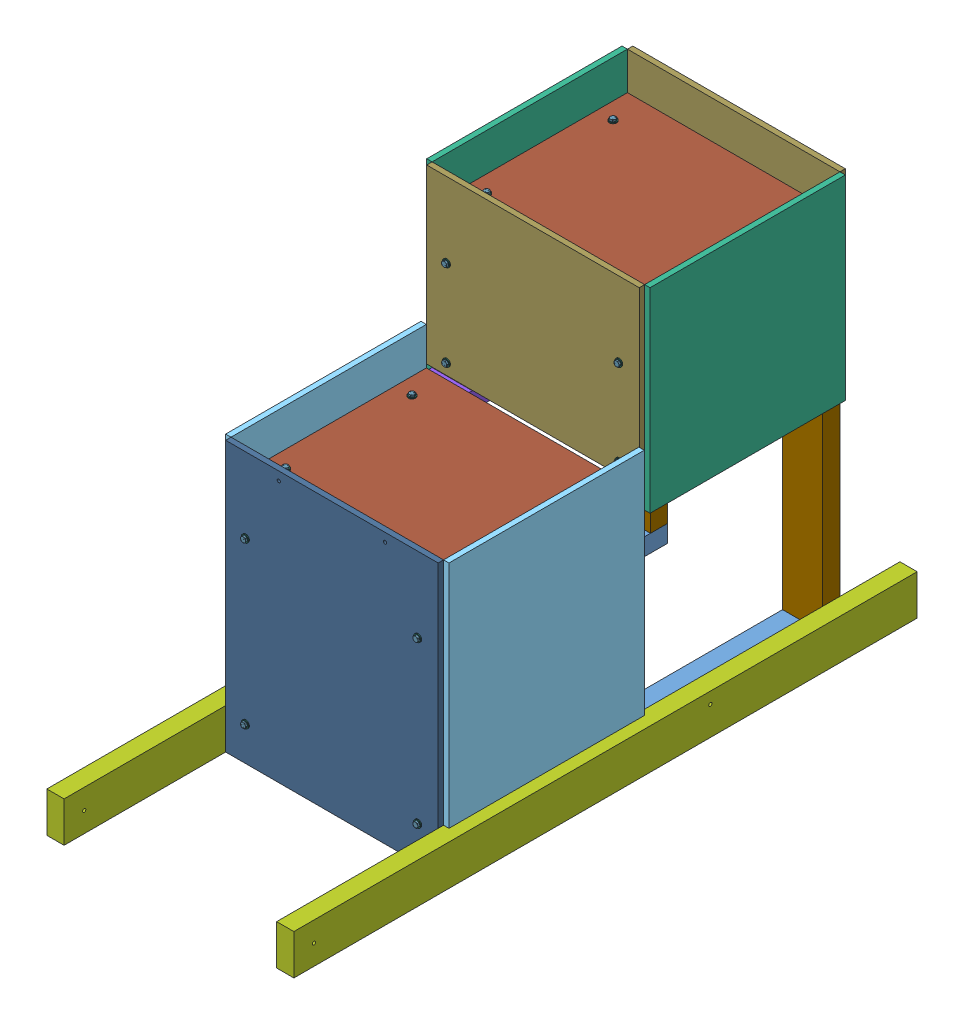
SolidWorks assembly Cube Shelf, configuration Default. Lengths in mm.
Overall size (546.1 901.7 1377.95).
85 component instances, 15 part files, 174 mates.
Components (placement in the parent):
- TE-23039-1: TE-23039 [Default] at (0 0 0.0635) size (127 901.7 1377.95)
  - TE-23018-1: TE-23018 [Default] at (44.45 19.05 -0.0635) x (0 -1 0) z (0 0 1) size (38.1 88.9 876.3)
  - TE-23019-1: TE-23019 [Default] at (44.45 469.9 857.1865) x (0 0 -1) z (0 -1 0) size (38.1 88.9 431.8)
  - TE-23023-1: TE-23023 [Default] at (44.45 793.75 -0.0635) x (0 -1 0) z (0 0 1) size (38.1 88.9 431.8)
  - TE-23022-1: TE-23022 [Default] at (44.45 508 412.6865) x (0 0 1) z (0 1 0) size (38.1 88.9 266.7)
  - TE-23024-1: TE-23024 [Default] at (-11.9062 342.9 660.3365) x (0 0 -1) z (0 -1 0) size (431.8 11.91 508)
  - TE-23025-1: TE-23025 [Default] at (-11.9062 685.8 215.8365) x (0 0 1) z (0 1 0) size (431.8 11.91 431.8)
  - TE-23005-1: TE-23005 [Default] at (-19.05 44.45 -132.6198) size (38.1 88.9 1377.95)
  - TE-23021-1: TE-23021 [Default] at (44.45 488.95 38.0365) x (0 1 0) z (0 0 1) size (38.1 88.9 838.2)
  - TE-23020-1: TE-23020 [Default] at (44.45 38.1 18.9865) x (0 0 -1) z (0 1 0) size (38.1 88.9 736.6)
- TE-23038-1: TE-23038 [Default] at (0 0 0.0635) size (127 901.7 1377.95)
  - TE-23018-1: TE-23018 [Default] at (425.45 19.05 -0.0635) x (0 -1 0) z (0 0 1) size (38.1 88.9 876.3)
  - TE-23019-1: TE-23019 [Default] at (425.45 38.1 857.1865) x (0 0 -1) z (0 1 0) size (38.1 88.9 431.8)
  - TE-23023-1: TE-23023 [Default] at (425.45 793.75 -0.0635) x (0 -1 0) z (0 0 1) size (38.1 88.9 431.8)
  - TE-23022-1: TE-23022 [Default] at (425.45 508 412.6865) x (0 0 1) z (0 1 0) size (38.1 88.9 266.7)
  - TE-23024-1: TE-23024 [Default] at (481.8062 342.9 660.3365) x (0 0 1) z (0 -1 0) size (431.8 11.91 508)
  - TE-23025-1: TE-23025 [Default] at (481.8062 685.8 215.8365) x (0 0 1) z (0 -1 0) size (431.8 11.91 431.8)
  - TE-23005-1: TE-23005 [Default] at (488.95 44.45 -132.6198) size (38.1 88.9 1377.95)
  - TE-23021-1: TE-23021 [Default] at (425.45 488.95 38.0365) x (0 1 0) z (0 0 1) size (38.1 88.9 838.2)
  - TE-23020-1: TE-23020 [Default] at (425.45 38.1 18.9865) x (0 0 -1) z (0 1 0) size (38.1 88.9 736.6)
- TE-23026-1: TE-23026 [Default] at (234.95 298.45 876.3) x (1 0 0) z (0 -1 0) size (469.9 11.91 596.9)
- TE-23027-1: TE-23027 [Default] at (234.95 508 660.4) size (457.2 11.91 419.1)
- TE-23028-1: TE-23028 [Default] at (234.95 711.2 431.8) size (469.9 381 11.91)
- TE-23028-2: TE-23028 [Default] at (234.95 711.2 -11.9062) size (469.9 381 11.91)
- TE-23027-2: TE-23027 [Default] at (234.95 812.8 215.9) size (457.2 11.91 419.1)
- TeeNut_.25_20-1: TeeNut_.25_20 [90975A025] at (425.45 736.6 392.5062) x (1 0 0) z (0 -1 0) size (19.05 9.53 19.05)
- TeeNut_.25_20-2: TeeNut_.25_20 [90975A025] at (425.45 546.1 392.5062) x (0.987351 0.158553 0) z (0.158553 -0.987351 0) size (19.05 9.53 19.05)
- TeeNut_.25_20-4: TeeNut_.25_20 [90975A025] at (425.45 773.5062 355.6) x (-0.994177 0 -0.107761) z (0.107761 0 -0.994177) size (19.05 9.53 19.05)
- TeeNut_.25_20-6: TeeNut_.25_20 [90975A025] at (425.45 773.5062 76.2) x (-0.972467 0 -0.233039) z (0.233039 0 -0.972467) size (19.05 9.53 19.05)
- TeeNut_.25_20-8: TeeNut_.25_20 [90975A025] at (425.45 736.6 39.2938) x (-0.642788 0.766044 0) z (-0.766044 -0.642788 0) size (19.05 9.53 19.05)
- TeeNut_.25_20-10: TeeNut_.25_20 [90975A025] at (425.45 468.7062 520.7) x (-0.089543 0 -0.995983) z (0.995983 0 -0.089543) size (19.05 9.53 19.05)
- TeeNut_.25_20-12: TeeNut_.25_20 [90975A025] at (425.45 468.7062 800.1) x (-0.194284 0 -0.980945) z (0.980945 0 -0.194284) size (19.05 9.53 19.05)
- TeeNut_.25_20-14: TeeNut_.25_20 [90975A025] at (425.45 431.8 837.0062) x (0.939693 0.34202 0) z (0.34202 -0.939693 0) size (19.05 9.53 19.05)
- TeeNut_.25_20-16: TeeNut_.25_20 [90975A025] at (425.45 76.2 837.0062) x (0.984808 0.173648 0) z (0.173648 -0.984808 0) size (19.05 9.53 19.05)
- TeeNut_.25_20-18: TeeNut_.25_20 [90975A025] at (44.45 76.2 837.0062) x (1 0 0) z (0 -1 0) size (19.05 9.53 19.05)
- TeeNut_.25_20-20: TeeNut_.25_20 [90975A025] at (44.45 431.8 837.0062) x (0.984808 -0.173648 0) z (-0.173648 -0.984808 0) size (19.05 9.53 19.05)
- TeeNut_.25_20-22: TeeNut_.25_20 [90975A025] at (44.45 468.7062 800.1) x (0.430036 0 -0.902812) z (0.902812 0 0.430036) size (19.05 9.53 19.05)
- TeeNut_.25_20-24: TeeNut_.25_20 [90975A025] at (44.45 468.7062 520.7) x (0.645562 0 -0.763708) z (0.763708 0 0.645562) size (19.05 9.53 19.05)
- TeeNut_.25_20-26: TeeNut_.25_20 [90975A025] at (44.45 546.1 392.5062) x (0.902849 -0.429957 0) z (-0.429957 -0.902849 0) size (19.05 9.53 19.05)
- TeeNut_.25_20-28: TeeNut_.25_20 [90975A025] at (44.45 736.6 392.5062) x (0.906989 -0.421154 0) z (-0.421154 -0.906989 0) size (19.05 9.53 19.05)
- TeeNut_.25_20-30: TeeNut_.25_20 [90975A025] at (44.45 773.5062 355.6) x (-0.404582 0 -0.914502) z (0.914502 0 -0.404582) size (19.05 9.53 19.05)
- TeeNut_.25_20-32: TeeNut_.25_20 [90975A025] at (44.45 773.5062 76.2) x (-0.712248 0 -0.701928) z (0.701928 0 -0.712248) size (19.05 9.53 19.05)
- TeeNut_.25_20-34: TeeNut_.25_20 [90975A025] at (44.45 736.6 39.2938) x (-0.173648 -0.984808 0) z (0.984808 -0.173648 0) size (19.05 9.53 19.05)
- TeeNut_.25_20-36: TeeNut_.25_20 [90975A025] at (44.45 546.1 39.2938) x (-0.923728 -0.383049 0) z (0.383049 -0.923728 0) size (19.05 9.53 19.05)
- TeeNut_.25_20-38: TeeNut_.25_20 [90975A025] at (425.45 546.1 39.2938) x (0.173648 -0.984808 0) z (0.984808 0.173648 0) size (19.05 9.53 19.05)
- hex_.25_20_2-2: hex_.25_20_2 [Default] at (425.45 546.1 9.4774) x (0 0 1) z (-0.763011 -0.646385 0) size (54.77 12.83 11.11)
- hex_.25_20_2-3: hex_.25_20_2 [Default] at (425.45 736.6 9.4774) x (0 0 1) z (0.496833 0.867846 0) size (54.77 12.83 11.11)
- hex_.25_20_2-4: hex_.25_20_2 [Default] at (44.45 546.1 9.4774) x (0 0 1) z (-0.44479 -0.895635 0) size (54.77 12.83 11.11)
- hex_.25_20_2-5: hex_.25_20_2 [Default] at (44.45 803.3226 76.2) x (0 -1 0) z (-0.809763 0 0.586757) size (54.77 12.83 11.11)
- hex_.25_20_2-6: hex_.25_20_2 [Default] at (425.45 431.8 866.8226) x (0 0 -1) z (-0.990347 -0.138607 0) size (54.77 12.83 11.11)
- hex_.25_20_2-7: hex_.25_20_2 [Default] at (425.45 76.2 866.8226) x (0 0 -1) z (0.745154 -0.666893 0) size (54.77 12.83 11.11)
- hex_.25_20_2-8: hex_.25_20_2 [Default] at (425.45 803.3226 76.2) x (0 -1 0) z (-0.954468 0 0.298314) size (54.77 12.83 11.11)
- hex_.25_20_2-9: hex_.25_20_2 [Default] at (44.45 76.2 866.8226) x (0 0 -1) z (-0.848403 -0.52935 0) size (54.77 12.83 11.11)
- hex_.25_20_2-10: hex_.25_20_2 [Default] at (44.45 431.8 866.8226) x (0 0 -1) z (0.285323 0.958431 0) size (54.77 12.83 11.11)
- hex_.25_20_2-11: hex_.25_20_2 [Default] at (425.45 498.5226 520.7) x (0 -1 0) z (0.273056 0 0.961998) size (54.77 12.83 11.11)
- hex_.25_20_2-12: hex_.25_20_2 [Default] at (425.45 498.5226 800.1) x (0 -1 0) z (-0.907887 0 0.419215) size (54.77 12.83 11.11)
- hex_.25_20_2-13: hex_.25_20_2 [Default] at (44.45 803.3226 355.6) x (0 -1 0) z (0.603096 0 0.797669) size (54.77 12.83 11.11)
- hex_.25_20_2-15: hex_.25_20_2 [Default] at (425.45 546.1 422.3226) x (0 0 -1) z (0.807696 -0.5896 0) size (54.77 12.83 11.11)
- hex_.25_20_2-16: hex_.25_20_2 [Default] at (44.45 498.5226 800.1) x (0 -1 0) z (0.961687 0 0.274151) size (54.77 12.83 11.11)
- hex_.25_20_2-17: hex_.25_20_2 [Default] at (44.45 498.5226 520.7) x (0 -1 0) z (-0.90705 0 0.421023) size (54.77 12.83 11.11)
- hex_.25_20_2-18: hex_.25_20_2 [Default] at (44.45 546.1 422.3226) x (0 0 -1) z (0.948389 -0.31711 0) size (54.77 12.83 11.11)
- hex_.25_20_2-19: hex_.25_20_2 [Default] at (425.45 803.3226 355.6) x (0 -1 0) z (-0.287086 0 0.957905) size (54.77 12.83 11.11)
- hex_.25_20_2-20: hex_.25_20_2 [Default] at (44.45 736.6 422.3226) x (0 0 -1) z (1 0 0) size (54.77 12.83 11.11)
- hex_.25_20_2-1: hex_.25_20_2 [Default] at (425.45 736.6 422.3226) x (0 0 -1) z (-0.132102 0.991236 0) size (54.77 12.83 11.11)
- washer_flat_.25-1: washer_flat_.25 [98023A029] at (425.45 736.6 -13.9383) x (1 0 0) z (0 -1 0) size (15.88 2.03 15.88)
- washer_flat_.25-2: washer_flat_.25 [98023A029] at (425.45 521.9383 520.7) x (-0.837169 0 -0.546944) z (-0.546944 0 0.837169) size (15.88 2.03 15.88)
- washer_flat_.25-3: washer_flat_.25 [98023A029] at (425.45 521.9383 800.1) x (-0.837169 0 -0.546944) z (-0.546944 0 0.837169) size (15.88 2.03 15.88)
- washer_flat_.25-4: washer_flat_.25 [98023A029] at (44.45 826.7382 355.6) x (-0.837169 0 -0.546944) z (-0.546944 0 0.837169) size (15.88 2.03 15.88)
- washer_flat_.25-5: washer_flat_.25 [98023A029] at (44.45 521.9383 520.7) x (-0.837169 0 -0.546944) z (-0.546944 0 0.837169) size (15.88 2.03 15.88)
- washer_flat_.25-6: washer_flat_.25 [98023A029] at (44.45 431.8 890.2382) x (1 0 0) z (0 1 0) size (15.88 2.03 15.88)
- washer_flat_.25-7: washer_flat_.25 [98023A029] at (425.45 736.6 445.7382) x (0.995174 0.098126 0) z (-0.098126 0.995174 0) size (15.88 2.03 15.88)
- washer_flat_.25-8: washer_flat_.25 [98023A029] at (425.45 826.7382 76.2) x (-0.837169 0 -0.546944) z (-0.546944 0 0.837169) size (15.88 2.03 15.88)
- washer_flat_.25-9: washer_flat_.25 [98023A029] at (44.45 826.7382 76.2) x (-0.837169 0 -0.546944) z (-0.546944 0 0.837169) size (15.88 2.03 15.88)
- washer_flat_.25-10: washer_flat_.25 [98023A029] at (425.45 546.1 -13.9383) x (1 0 0) z (0 -1 0) size (15.88 2.03 15.88)
- washer_flat_.25-11: washer_flat_.25 [98023A029] at (44.45 546.1 -13.9383) x (1 0 0) z (0 -1 0) size (15.88 2.03 15.88)
- washer_flat_.25-12: washer_flat_.25 [98023A029] at (44.45 736.6 -13.9383) x (1 0 0) z (0 -1 0) size (15.88 2.03 15.88)
- washer_flat_.25-13: washer_flat_.25 [98023A029] at (425.45 431.8 890.2382) x (1 0 0) z (0 1 0) size (15.88 2.03 15.88)
- washer_flat_.25-14: washer_flat_.25 [98023A029] at (44.45 521.9383 800.1) x (-0.837169 0 -0.546944) z (-0.546944 0 0.837169) size (15.88 2.03 15.88)
- washer_flat_.25-15: washer_flat_.25 [98023A029] at (44.45 76.2 890.2382) x (1 0 0) z (0 1 0) size (15.88 2.03 15.88)
- washer_flat_.25-16: washer_flat_.25 [98023A029] at (425.45 826.7382 355.6) x (-0.837169 0 -0.546944) z (-0.546944 0 0.837169) size (15.88 2.03 15.88)
- washer_flat_.25-17: washer_flat_.25 [98023A029] at (425.45 76.2 890.2382) x (1 0 0) z (0 1 0) size (15.88 2.03 15.88)
- washer_flat_.25-18: washer_flat_.25 [98023A029] at (425.45 546.1 445.7382) x (0.860134 -0.510068 0) z (0.510068 0.860134 0) size (15.88 2.03 15.88)
- washer_flat_.25-19: washer_flat_.25 [98023A029] at (44.45 546.1 445.7382) x (1 0 0) z (0 1 0) size (15.88 2.03 15.88)
- washer_flat_.25-20: washer_flat_.25 [98023A029] at (44.45 736.6 445.7382) x (0.975112 0.221713 0) z (-0.221713 0.975112 0) size (15.88 2.03 15.88)
- hex_.25_20_2-21: hex_.25_20_2 [Default] at (44.45 736.6 9.4774) x (0 0 1) z (0.942994 -0.332808 0) size (54.77 12.83 11.11)
Mates (geometry in assembly coordinates):
- Distance5: distance = 6.35 mm anti-aligned: plane of TE-23026-1 through (234.95 298.45 876.3) normal (0 0 -1); plane of Cube Shelf Platform-1 through (6.35 519.9062 869.95) normal (0 0 1)
- Coincident83: coincident aligned: plane of Cube Shelf Upper Front Panel-1 through (0 901.7 443.7063) normal (0 1 0); plane of Cube Shelf Upper Front Panel-2 through (0 901.7 0) normal (0 1 0)
- Coincident159: coincident anti-aligned: plane of Cube Shelf Right Side Frame-1/Cube Shelf Long Horizontal-1 through (0 0 876.3) normal (0 -1 0)
- Coincident160: coincident anti-aligned: plane of Cube Shelf Right Side Frame-1/Cube Shelf Long Horizontal-1 through (0 38.1 876.3) normal (-1 0 0)
- Coincident161: coincident anti-aligned: plane of Cube Shelf Right Side Frame-1/Cube Shelf Long Horizontal-1 through (44.45 19.05 0) normal (0 0 -1)
- Coincident162: coincident aligned: plane of Cube Shelf Right Side Frame-1/Cube Shelf Long Horizontal-1 through (0 0 876.3) normal (0 -1 0); plane of TE-23026-1 through (0 0 888.2062) normal (0 -1 0)
- Coincident163: coincident anti-aligned: plane of TE-23039-1/TE-23019-1 through (0 38.1 876.3) normal (0 0 1); plane of TE-23026-1 through (234.95 298.45 876.3) normal (0 0 -1)
- Coincident164: coincident aligned: plane of TE-23039-1/TE-23019-1 through (0 38.1 876.3) normal (-1 0 0); plane of TE-23026-1 through (0 0 888.2062) normal (-1 0 0)
- Distance12: distance = 6.35 mm anti-aligned: plane of Cube Shelf Platform-1 through (6.35 519.9062 869.95) normal (-1 0 0); plane of TE-23039-1/TE-23024-1 through (0 342.9 660.4) normal (1 0 0)
- Coincident166: coincident aligned: plane of Cube Shelf Upper Front Panel-1 through (0 901.7 443.7063) normal (0 1 0); plane of TE-23039-1/TE-23025-1 through (0 901.7 0) normal (0 1 0)
- Coincident167: coincident anti-aligned: plane of Cube Shelf Upper Front Panel-2 through (234.95 711.2 0) normal (0 0 1); plane of TE-23039-1/TE-23025-1 through (0 901.7 0) normal (0 0 -1)
- Coincident168: coincident anti-aligned: plane of Cube Shelf Upper Front Panel-1 through (234.95 711.2 431.8) normal (0 0 -1); plane of TE-23039-1/TE-23025-1 through (0 901.7 431.8) normal (0 0 1)
- Coincident181: coincident aligned: plane of Assem7^Cube Shelf-1/Copy of Assem6^Assem7_Cube Shelf-1/Cube Shelf Long Horizontal-1 through (381 0 876.3) normal (0 -1 0); plane of TE-23026-1 through (0 0 888.2062) normal (0 -1 0)
- Coincident182: coincident anti-aligned: plane of Assem7^Cube Shelf-1/Copy of Assem6^Assem7_Cube Shelf-1/Cube Shelf Long Vertical-1 through (469.9 482.6 876.3) normal (0 0 1); plane of TE-23026-1 through (234.95 298.45 876.3) normal (0 0 -1)
- Coincident183: coincident aligned: plane of Assem7^Cube Shelf-1/Copy of Assem6^Assem7_Cube Shelf-1/Cube Shelf Short Horizontal-1 through (469.9 812.8 431.8) normal (1 0 0); plane of TE-23028-2 through (469.9 520.7 0) normal (1 0 0)
- Coincident184: coincident anti-aligned: plane of Assem7^Cube Shelf-1/Copy of Assem6^Assem7_Cube Shelf-1/Cube Shelf Short Horizontal-1 through (381 812.8 431.8) normal (0 1 0); plane of GE-23651-2 through (234.95 812.8 215.9) normal (0 -1 0)
- Concentric5: concentric anti-aligned: cylinder of Assem7^Cube Shelf-1/Copy of Assem6^Assem7_Cube Shelf-1/Cube Shelf Short Horizontal-1 through (425.45 774.7 76.2) axis (0 -1 0) radius 3.9688; cylinder of GE-23651-2 through (425.45 824.7062 76.2) axis (0 1 0) radius 3.5719
- Coincident185: coincident anti-aligned: plane of Assem7^Cube Shelf-1/Copy of Assem6^Assem7_Cube Shelf-1/Cube Shelf Short Vertical-1 through (381 774.7 431.8) normal (0 0 1); plane of TE-23028-1 through (234.95 711.2 431.8) normal (0 0 -1)
- Coincident186: coincident aligned: plane of Assem7^Cube Shelf-1/Copy of Assem6^Assem7_Cube Shelf-1/Cube Shelf Short Vertical-1 through (469.9 774.7 393.7) normal (1 0 0); plane of TE-23028-1 through (469.9 520.7 443.7063) normal (1 0 0)
- Coincident187: coincident anti-aligned: plane of TE-23028-1 through (234.95 711.2 443.7063) normal (0 0 1); plane of Assem7^Cube Shelf-1/Copy of Assem6^Assem7_Cube Shelf-1/Cube Shelf Lower Side Panel-1 through (469.9 88.9 443.7063) normal (0 0 -1)
- Coincident188: coincident aligned: plane of TE-23028-2 through (0 901.7 0) normal (0 1 0); plane of Assem7^Cube Shelf-1/Copy of Assem6^Assem7_Cube Shelf-1/Cube Shelf Upper Side Panel-1 through (469.9 901.7 0) normal (0 1 0)
- Coincident189: coincident anti-aligned: plane of TE-23028-2 through (234.95 711.2 0) normal (0 0 1); plane of Assem7^Cube Shelf-1/Copy of Assem6^Assem7_Cube Shelf-1/Cube Shelf Upper Side Panel-1 through (469.9 482.6 0) normal (0 0 -1)
- Coincident190: coincident anti-aligned: plane of TE-23026-1 through (469.9 0 888.2062) normal (1 0 0); plane of Assem7^Cube Shelf-1/Copy of Assem6^Assem7_Cube Shelf-1/Cone Ramp Horizontal no holes-1 through (469.9 0 1245.3302) normal (-1 0 0)
- Concentric7: concentric anti-aligned: cylinder of Cube Shelf Left Side Frame-1/Copy of Assem6^Cube Shelf Left Side Frame-1/Cube Shelf Short Vertical-1 through (425.45 736.6 431.8) axis (0 0 1) radius 3.9688; cylinder of TeeNut_.25_20-1 through (425.45 736.6 401.6375) axis (0 0 -1) radius 3.8735
- Coincident191: coincident anti-aligned: plane of Cube Shelf Left Side Frame-1/Copy of Assem6^Cube Shelf Left Side Frame-1/Cube Shelf Short Vertical-1 through (381 774.7 393.7) normal (0 0 -1); plane of TeeNut_.25_20-1 through (425.45 736.6 393.7) normal (0 0 1)
- Coincident192: coincident anti-aligned: plane of Cube Shelf Left Side Frame-1/Copy of Assem6^Cube Shelf Left Side Frame-1/Cube Shelf Long Horizontal top-1 through (469.9 520.7 876.3) normal (0 1 0); plane of TE-23027-1 through (234.95 508 660.4) normal (0 -1 0)
- Concentric8: concentric anti-aligned: cylinder of Cube Shelf Left Side Frame-1/Copy of Assem6^Cube Shelf Left Side Frame-1/Cube Shelf Short Vertical-1 through (425.45 558.8 431.8) axis (0 0 1) radius 3.9688; cylinder of TeeNut_.25_20-2 through (425.45 546.1 401.6375) axis (0 0 -1) radius 3.8735
- Coincident193: coincident anti-aligned: plane of Cube Shelf Left Side Frame-1/Copy of Assem6^Cube Shelf Left Side Frame-1/Cube Shelf Short Vertical-1 through (381 774.7 393.7) normal (0 0 -1); plane of TeeNut_.25_20-2 through (425.45 546.1 393.7) normal (0 0 1)
- Concentric9: concentric aligned: cylinder of Cube Shelf Left Side Frame-1/Copy of Assem6^Cube Shelf Left Side Frame-1/Cube Shelf Short Horizontal-1 through (425.45 774.7 355.6) axis (0 -1 0) radius 3.9688; cylinder of TeeNut_.25_20-4 through (425.45 782.6375 355.6) axis (0 -1 0) radius 3.8735
- Coincident194: coincident anti-aligned: plane of Cube Shelf Left Side Frame-1/Copy of Assem6^Cube Shelf Left Side Frame-1/Cube Shelf Short Horizontal-1 through (381 774.7 431.8) normal (0 -1 0); plane of TeeNut_.25_20-4 through (425.45 774.7 355.6) normal (0 1 0)
- Concentric10: concentric aligned: cylinder of Cube Shelf Left Side Frame-1/Copy of Assem6^Cube Shelf Left Side Frame-1/Cube Shelf Short Horizontal-1 through (425.45 774.7 76.2) axis (0 -1 0) radius 3.9688; cylinder of TeeNut_.25_20-6 through (425.45 782.6375 76.2) axis (0 -1 0) radius 3.8735
- Coincident195: coincident anti-aligned: plane of Cube Shelf Left Side Frame-1/Copy of Assem6^Cube Shelf Left Side Frame-1/Cube Shelf Short Horizontal-1 through (381 774.7 431.8) normal (0 -1 0); plane of TeeNut_.25_20-6 through (425.45 774.7 76.2) normal (0 1 0)
- Concentric11: concentric anti-aligned: cylinder of Cube Shelf Left Side Frame-1/Copy of Assem6^Cube Shelf Left Side Frame-1/Back CS uprights-1 through (425.45 736.6 0) axis (0 0 -1) radius 3.9688; cylinder of TeeNut_.25_20-8 through (425.45 736.6 30.1625) axis (0 0 1) radius 3.8735
- Coincident196: coincident anti-aligned: plane of Cube Shelf Left Side Frame-1/Copy of Assem6^Cube Shelf Left Side Frame-1/Back CS uprights-1 through (469.9 774.7 38.1) normal (0 0 1); plane of TeeNut_.25_20-8 through (425.45 736.6 38.1) normal (0 0 -1)
- Concentric12: concentric anti-aligned: cylinder of Cube Shelf Left Side Frame-1/Copy of Assem6^Cube Shelf Left Side Frame-1/Cube Shelf Long Horizontal top-1 through (425.45 520.7 520.7) axis (0 1 0) radius 3.9688; cylinder of TeeNut_.25_20-10 through (425.45 477.8375 520.7) axis (0 -1 0) radius 3.8735
- Coincident197: coincident anti-aligned: plane of Cube Shelf Left Side Frame-1/Copy of Assem6^Cube Shelf Left Side Frame-1/Cube Shelf Long Horizontal top-1 through (469.9 482.6 876.3) normal (0 -1 0); plane of TeeNut_.25_20-10 through (425.45 469.9 520.7) normal (0 1 0)
- Concentric13: concentric anti-aligned: cylinder of Cube Shelf Left Side Frame-1/Copy of Assem6^Cube Shelf Left Side Frame-1/Cube Shelf Long Horizontal top-1 through (425.45 520.7 800.1) axis (0 1 0) radius 3.9688; cylinder of TeeNut_.25_20-12 through (425.45 477.8375 800.1) axis (0 -1 0) radius 3.8735
- Coincident198: coincident anti-aligned: plane of Cube Shelf Left Side Frame-1/Copy of Assem6^Cube Shelf Left Side Frame-1/Cube Shelf Long Horizontal top-1 through (469.9 482.6 876.3) normal (0 -1 0); plane of TeeNut_.25_20-12 through (425.45 469.9 800.1) normal (0 1 0)
- Concentric14: concentric aligned: cylinder of Cube Shelf Left Side Frame-1/Copy of Assem6^Cube Shelf Left Side Frame-1/Cube Shelf Long Vertical-1 through (425.45 444.5 838.2) axis (0 0 -1) radius 3.9688; cylinder of TeeNut_.25_20-14 through (425.45 431.8 846.1375) axis (0 0 -1) radius 3.8735
- Coincident199: coincident anti-aligned: plane of Cube Shelf Left Side Frame-1/Copy of Assem6^Cube Shelf Left Side Frame-1/Cube Shelf Long Vertical-1 through (469.9 482.6 838.2) normal (0 0 -1); plane of TeeNut_.25_20-14 through (425.45 431.8 838.2) normal (0 0 1)
- Concentric15: concentric aligned: cylinder of Cube Shelf Left Side Frame-1/Copy of Assem6^Cube Shelf Left Side Frame-1/Cube Shelf Long Vertical-1 through (425.45 76.2 838.2) axis (0 0 -1) radius 3.9688; cylinder of TeeNut_.25_20-16 through (425.45 76.2 846.1375) axis (0 0 -1) radius 3.8735
- Coincident200: coincident anti-aligned: plane of Cube Shelf Left Side Frame-1/Copy of Assem6^Cube Shelf Left Side Frame-1/Cube Shelf Long Vertical-1 through (469.9 482.6 838.2) normal (0 0 -1); plane of TeeNut_.25_20-16 through (425.45 76.2 838.2) normal (0 0 1)
- Concentric16: concentric aligned: cylinder of TE-23039-1/TE-23019-1 through (44.45 76.2 838.2) axis (0 0 -1) radius 3.9688; cylinder of TeeNut_.25_20-18 through (44.45 76.2 846.1375) axis (0 0 -1) radius 3.8735
- Coincident201: coincident anti-aligned: plane of TE-23039-1/TE-23019-1 through (0 38.1 838.2) normal (0 0 -1); plane of TeeNut_.25_20-18 through (44.45 76.2 838.2) normal (0 0 1)
- Concentric17: concentric aligned: cylinder of TE-23039-1/TE-23019-1 through (44.45 431.8 838.2) axis (0 0 -1) radius 3.9688; cylinder of TeeNut_.25_20-20 through (44.45 431.8 846.1375) axis (0 0 -1) radius 3.8735
- Coincident202: coincident anti-aligned: plane of TE-23039-1/TE-23019-1 through (0 38.1 838.2) normal (0 0 -1); plane of TeeNut_.25_20-20 through (44.45 431.8 838.2) normal (0 0 1)
- Concentric18: concentric anti-aligned: cylinder of TE-23039-1/TE-23021-1 through (44.45 508 800.1) axis (0 1 0) radius 3.9688; cylinder of TeeNut_.25_20-22 through (44.45 477.8375 800.1) axis (0 -1 0) radius 3.8735
- Coincident203: coincident anti-aligned: plane of TE-23039-1/TE-23021-1 through (88.9 469.9 876.3) normal (0 -1 0); plane of TeeNut_.25_20-22 through (44.45 469.9 800.1) normal (0 1 0)
- Concentric19: concentric anti-aligned: cylinder of TE-23039-1/TE-23021-1 through (44.45 508 520.7) axis (0 1 0) radius 3.9688; cylinder of TeeNut_.25_20-24 through (44.45 477.8375 520.7) axis (0 -1 0) radius 3.8735
- Coincident204: coincident anti-aligned: plane of TE-23039-1/TE-23021-1 through (88.9 469.9 876.3) normal (0 -1 0); plane of TeeNut_.25_20-24 through (44.45 469.9 520.7) normal (0 1 0)
- Concentric20: concentric anti-aligned: cylinder of TE-23039-1/TE-23022-1 through (44.45 546.1 431.8) axis (0 0 1) radius 3.9688; cylinder of TeeNut_.25_20-26 through (44.45 546.1 401.6375) axis (0 0 -1) radius 3.8735
- Coincident205: coincident anti-aligned: plane of TE-23039-1/TE-23022-1 through (0 774.7 393.7) normal (0 0 -1); plane of TeeNut_.25_20-26 through (44.45 546.1 393.7) normal (0 0 1)
- Concentric21: concentric anti-aligned: cylinder of TE-23039-1/TE-23022-1 through (44.45 736.6 431.8) axis (0 0 1) radius 3.9688; cylinder of TeeNut_.25_20-28 through (44.45 736.6 401.6375) axis (0 0 -1) radius 3.8735
- Coincident206: coincident anti-aligned: plane of TE-23039-1/TE-23022-1 through (0 774.7 393.7) normal (0 0 -1); plane of TeeNut_.25_20-28 through (44.45 736.6 393.7) normal (0 0 1)
- Concentric22: concentric aligned: cylinder of Cube Shelf Right Side Frame-1/Cube Shelf Short Horizontal-1 through (44.45 774.7 355.6) axis (0 -1 0) radius 3.9688; cylinder of TeeNut_.25_20-30 through (44.45 782.6375 355.6) axis (0 -1 0) radius 3.8735
- Coincident207: coincident anti-aligned: plane of Cube Shelf Right Side Frame-1/Cube Shelf Short Horizontal-1 through (0 774.7 431.8) normal (0 -1 0); plane of TeeNut_.25_20-30 through (44.45 774.7 355.6) normal (0 1 0)
- Concentric23: concentric aligned: cylinder of Cube Shelf Right Side Frame-1/Cube Shelf Short Horizontal-1 through (44.45 774.7 76.2) axis (0 -1 0) radius 3.9688; cylinder of TeeNut_.25_20-32 through (44.45 782.6375 76.2) axis (0 -1 0) radius 3.8735
- Coincident208: coincident anti-aligned: plane of Cube Shelf Right Side Frame-1/Cube Shelf Short Horizontal-1 through (0 774.7 431.8) normal (0 -1 0); plane of TeeNut_.25_20-32 through (44.45 774.7 76.2) normal (0 1 0)
- Concentric24: concentric anti-aligned: cylinder of Cube Shelf Right Side Frame-1/Back CS uprights-1 through (44.45 736.6 0) axis (0 0 -1) radius 3.9688; cylinder of TeeNut_.25_20-34 through (44.45 736.6 30.1625) axis (0 0 1) radius 3.8735
- Coincident209: coincident anti-aligned: plane of Cube Shelf Right Side Frame-1/Back CS uprights-1 through (88.9 774.7 38.1) normal (0 0 1); plane of TeeNut_.25_20-34 through (44.45 736.6 38.1) normal (0 0 -1)
- Concentric25: concentric anti-aligned: cylinder of Cube Shelf Right Side Frame-1/Back CS uprights-1 through (44.45 546.1 0) axis (0 0 -1) radius 3.9688; cylinder of TeeNut_.25_20-36 through (44.45 546.1 30.1625) axis (0 0 1) radius 3.8735
- Coincident210: coincident anti-aligned: plane of Cube Shelf Right Side Frame-1/Back CS uprights-1 through (88.9 774.7 38.1) normal (0 0 1); plane of TeeNut_.25_20-36 through (44.45 546.1 38.1) normal (0 0 -1)
- Concentric26: concentric anti-aligned: cylinder of Cube Shelf Left Side Frame-1/Copy of Assem6^Cube Shelf Left Side Frame-1/Back CS uprights-1 through (425.45 558.8 0) axis (0 0 -1) radius 3.9688; cylinder of TeeNut_.25_20-38 through (425.45 546.1 30.1625) axis (0 0 1) radius 3.8735
- Coincident211: coincident anti-aligned: plane of Cube Shelf Left Side Frame-1/Copy of Assem6^Cube Shelf Left Side Frame-1/Back CS uprights-1 through (469.9 774.7 38.1) normal (0 0 1); plane of TeeNut_.25_20-38 through (425.45 546.1 38.1) normal (0 0 -1)
- Coincident232: coincident anti-aligned: plane of TE-23038-1/TE-23021-1 through (469.9 508 876.3) normal (0 1 0); plane of TE-23027-1 through (234.95 508 660.4) normal (0 -1 0)
- Coincident233: coincident anti-aligned: plane of TE-23039-1/TE-23021-1 through (88.9 508 876.3) normal (0 1 0); plane of TE-23027-1 through (234.95 508 660.4) normal (0 -1 0)
- Coincident234: coincident anti-aligned: plane of TE-23039-1/TE-23025-1 through (0 685.8 215.9) normal (1 0 0); plane of Cube Shelf Upper Front Panel-1 through (0 520.7 443.7063) normal (-1 0 0)
- Coincident235: coincident anti-aligned: plane of Cube Shelf Right Side Frame-1/Cube Shelf Short Horizontal-1 through (0 812.8 431.8) normal (0 1 0); plane of GE-23651-2 through (234.95 812.8 215.9) normal (0 -1 0)
- Coincident237: coincident anti-aligned: plane of TE-23039-1/TE-23025-1 through (0 685.8 215.9) normal (1 0 0); plane of Cube Shelf Upper Front Panel-2 through (0 520.7 0) normal (-1 0 0)
- Coincident238: coincident aligned: plane of Cube Shelf Right Side Frame-1/Cone Ramp Horizontal no holes-1 through (-19.05 44.45 -132.5562) normal (0 0 -1); plane of Cube Shelf Left Side Frame-1/Cone Ramp Horizontal no holes-1 through (488.95 44.45 -132.5562) normal (0 0 -1)
- Coincident239: coincident aligned: plane of Cube Shelf Right Side Frame-1/Cone Ramp Horizontal no holes-1 through (-38.1 0 1245.3938) normal (0 -1 0); plane of Cube Shelf Left Side Frame-1/Cone Ramp Horizontal no holes-1 through (469.9 0 1245.3938) normal (0 -1 0)
- Coincident240: coincident anti-aligned: plane of TE-23038-1/TE-23024-1 through (469.9 342.9 660.4) normal (-1 0 0); plane of TE-23026-1 through (469.9 0 888.2062) normal (1 0 0)
- Concentric50: concentric anti-aligned: cylinder of Cube Shelf Left Side Frame-1/Back CS uprights-1 through (425.45 546.1 0) axis (0 0 -1) radius 3.9688; cylinder of TeeNut_.25_20-38 through (425.45 546.1 30.1625) axis (0 0 1) radius 3.8735
- Coincident241: coincident anti-aligned: plane of Cube Shelf Left Side Frame-1/Back CS uprights-1 through (469.9 774.7 38.1) normal (0 0 1); plane of TeeNut_.25_20-38 through (425.45 546.1 38.1) normal (0 0 -1)
- Concentric51: concentric anti-aligned: cylinder of TE-23038-1/TE-23022-1 through (425.45 736.6 431.8) axis (0 0 1) radius 3.9688; cylinder of TeeNut_.25_20-1 through (425.45 736.6 401.6375) axis (0 0 -1) radius 3.8735
- Coincident242: coincident anti-aligned: plane of TE-23038-1/TE-23022-1 through (381 774.7 393.7) normal (0 0 -1); plane of TeeNut_.25_20-1 through (425.45 736.6 393.7) normal (0 0 1)
- Concentric52: concentric anti-aligned: cylinder of TE-23038-1/TE-23022-1 through (425.45 546.1 431.8) axis (0 0 1) radius 3.9688; cylinder of TeeNut_.25_20-2 through (425.45 546.1 401.6375) axis (0 0 -1) radius 3.8735
- Coincident243: coincident anti-aligned: plane of TE-23038-1/TE-23022-1 through (381 774.7 393.7) normal (0 0 -1); plane of TeeNut_.25_20-2 through (425.45 546.1 393.7) normal (0 0 1)
- Concentric53: concentric aligned: cylinder of GE-23640-1/GE-23647-1 through (425.45 774.7 355.6) axis (0 -1 0) radius 3.9688; cylinder of TeeNut_.25_20-4 through (425.45 782.6375 355.6) axis (0 -1 0) radius 3.8735
- Coincident244: coincident anti-aligned: plane of GE-23640-1/GE-23647-1 through (381 774.7 431.8) normal (0 -1 0); circle of TeeNut_.25_20-4
- Concentric54: concentric aligned: cylinder of GE-23640-1/GE-23647-1 through (425.45 774.7 76.2) axis (0 -1 0) radius 3.9688; cylinder of TeeNut_.25_20-6 through (425.45 782.6375 76.2) axis (0 -1 0) radius 3.8735
- Coincident245: coincident anti-aligned: plane of GE-23640-1/GE-23647-1 through (381 774.7 431.8) normal (0 -1 0); circle of TeeNut_.25_20-6
- Concentric55: concentric anti-aligned: cylinder of GE-23640-1/GE-23644-1 through (425.45 736.6 0) axis (0 0 -1) radius 3.9688; cylinder of TeeNut_.25_20-8 through (425.45 736.6 30.1625) axis (0 0 1) radius 3.8735
- Coincident246: coincident anti-aligned: plane of GE-23640-1/GE-23644-1 through (469.9 774.7 38.1) normal (0 0 1); circle of TeeNut_.25_20-8
- Concentric56: concentric anti-aligned: cylinder of TE-23038-1/TE-23021-1 through (425.45 508 800.1) axis (0 1 0) radius 3.9688; cylinder of TeeNut_.25_20-12 through (425.45 477.8375 800.1) axis (0 -1 0) radius 3.8735
- Coincident247: coincident anti-aligned: plane of TE-23038-1/TE-23021-1 through (469.9 469.9 876.3) normal (0 -1 0); circle of TeeNut_.25_20-12
- Concentric57: concentric aligned: cylinder of TE-23038-1/TE-23019-1 through (425.45 431.8 838.2) axis (0 0 -1) radius 3.9688; cylinder of TeeNut_.25_20-14 through (425.45 431.8 846.1375) axis (0 0 -1) radius 3.8735
- Coincident248: coincident anti-aligned: plane of TE-23038-1/TE-23019-1 through (469.9 469.9 838.2) normal (0 0 -1); circle of TeeNut_.25_20-14
- Concentric58: concentric aligned: cylinder of TE-23038-1/TE-23019-1 through (425.45 76.2 838.2) axis (0 0 -1) radius 3.9688; cylinder of TeeNut_.25_20-16 through (425.45 76.2 846.1375) axis (0 0 -1) radius 3.8735
- Coincident249: coincident anti-aligned: plane of TE-23038-1/TE-23019-1 through (469.9 469.9 838.2) normal (0 0 -1); circle of TeeNut_.25_20-16
- Concentric59: concentric anti-aligned: cylinder of TE-23038-1/TE-23021-1 through (425.45 508 520.7) axis (0 1 0) radius 3.9688; cylinder of TeeNut_.25_20-10 through (425.45 477.8375 520.7) axis (0 -1 0) radius 3.8735
- Coincident250: coincident anti-aligned: plane of TE-23038-1/TE-23021-1 through (469.9 469.9 876.3) normal (0 -1 0); circle of TeeNut_.25_20-10
- Concentric60: concentric anti-aligned: cylinder of GE-23652-1 through (44.45 736.6 443.7063) axis (0 0 1) radius 3.5719; cylinder of hex_.25_20_2-20 through (44.45 736.6 445.7382) axis (0 0 -1) radius 3.175
- Concentric61: concentric anti-aligned: cylinder of GE-23652-1 through (44.45 736.6 443.7063) axis (0 0 1) radius 3.5719; cylinder of washer_flat_.25-20 through (44.45 736.6 445.7382) axis (0 0 -1) radius 3.5687
- Coincident252: coincident anti-aligned: plane of GE-23652-1 through (234.95 711.2 443.7063) normal (0 0 1); circle of washer_flat_.25-20
- Coincident253: coincident anti-aligned: plane of hex_.25_20_2-20 through (50.0063 739.8079 445.7382) normal (0 0 -1); plane of washer_flat_.25-20 through (44.45 736.6 445.7382) normal (0 0 1)
- Concentric62: concentric anti-aligned: cylinder of GE-23652-1 through (425.45 736.6 443.7063) axis (0 0 1) radius 3.5719; cylinder of washer_flat_.25-7 through (425.45 736.6 445.7382) axis (0 0 -1) radius 3.5687
- Coincident254: coincident anti-aligned: plane of GE-23652-1 through (234.95 711.2 443.7063) normal (0 0 1); plane of washer_flat_.25-7 through (425.45 736.6 443.7063) normal (0 0 -1)
- Concentric63: concentric anti-aligned: cylinder of GE-23652-1 through (44.45 546.1 443.7063) axis (0 0 1) radius 3.5719; cylinder of washer_flat_.25-19 through (44.45 546.1 445.7382) axis (0 0 -1) radius 3.5687
- Coincident255: coincident anti-aligned: plane of GE-23652-1 through (234.95 711.2 443.7063) normal (0 0 1); circle of washer_flat_.25-19
- Concentric64: concentric anti-aligned: cylinder of GE-23652-1 through (425.45 546.1 443.7063) axis (0 0 1) radius 3.5719; cylinder of washer_flat_.25-18 through (425.45 546.1 445.7382) axis (0 0 -1) radius 3.5687
- Coincident256: coincident anti-aligned: plane of GE-23652-1 through (234.95 711.2 443.7063) normal (0 0 1); circle of washer_flat_.25-18
- Coincident257: coincident anti-aligned: plane of TE-23026-1 through (234.95 298.45 888.2062) normal (0 0 1); plane of washer_flat_.25-6 through (44.45 431.8 888.2062) normal (0 0 -1)
- Coincident258: coincident anti-aligned: plane of TE-23026-1 through (234.95 298.45 888.2062) normal (0 0 1); plane of washer_flat_.25-17 through (425.45 76.2 888.2062) normal (0 0 -1)
- Coincident259: coincident anti-aligned: plane of TE-23026-1 through (234.95 298.45 888.2062) normal (0 0 1); plane of washer_flat_.25-13 through (425.45 431.8 888.2062) normal (0 0 -1)
- Coincident260: coincident anti-aligned: plane of TE-23026-1 through (234.95 298.45 888.2062) normal (0 0 1); plane of washer_flat_.25-15 through (44.45 76.2 888.2062) normal (0 0 -1)
- Concentric65: concentric anti-aligned: cylinder of TE-23026-1 through (44.45 431.8 888.2062) axis (0 0 1) radius 3.5719; cylinder of washer_flat_.25-6 through (44.45 431.8 890.2382) axis (0 0 -1) radius 3.5687
- Concentric66: concentric anti-aligned: cylinder of TE-23026-1 through (425.45 431.8 888.2062) axis (0 0 1) radius 3.5719; cylinder of washer_flat_.25-13 through (425.45 431.8 890.2382) axis (0 0 -1) radius 3.5687
- Concentric67: concentric anti-aligned: cylinder of TE-23026-1 through (44.45 76.2 888.2062) axis (0 0 1) radius 3.5719; cylinder of washer_flat_.25-15 through (44.45 76.2 890.2382) axis (0 0 -1) radius 3.5687
- Concentric68: concentric anti-aligned: cylinder of TE-23026-1 through (425.45 76.2 888.2062) axis (0 0 1) radius 3.5719; cylinder of washer_flat_.25-17 through (425.45 76.2 890.2382) axis (0 0 -1) radius 3.5687
- Coincident261: coincident anti-aligned: plane of GE-23652-2 through (234.95 711.2 -11.9062) normal (0 0 -1); plane of washer_flat_.25-1 through (425.45 736.6 -11.9062) normal (0 0 1)
- Coincident262: coincident anti-aligned: plane of GE-23652-2 through (234.95 711.2 -11.9062) normal (0 0 -1); plane of washer_flat_.25-12 through (44.45 736.6 -11.9062) normal (0 0 1)
- Coincident263: coincident anti-aligned: plane of GE-23652-2 through (234.95 711.2 -11.9062) normal (0 0 -1); plane of washer_flat_.25-11 through (44.45 546.1 -11.9062) normal (0 0 1)
- Coincident264: coincident anti-aligned: plane of GE-23652-2 through (234.95 711.2 -11.9062) normal (0 0 -1); plane of washer_flat_.25-10 through (425.45 546.1 -11.9062) normal (0 0 1)
- Coincident265: coincident anti-aligned: plane of GE-23651-2 through (234.95 824.7062 215.9) normal (0 1 0); plane of washer_flat_.25-8 through (425.45 824.7062 76.2) normal (0 -1 0)
- Coincident266: coincident anti-aligned: plane of GE-23651-2 through (234.95 824.7062 215.9) normal (0 1 0); plane of washer_flat_.25-9 through (44.45 824.7062 76.2) normal (0 -1 0)
- Coincident267: coincident anti-aligned: plane of GE-23651-2 through (234.95 824.7062 215.9) normal (0 1 0); plane of washer_flat_.25-4 through (44.45 824.7062 355.6) normal (0 -1 0)
- Coincident268: coincident anti-aligned: plane of GE-23651-2 through (234.95 824.7062 215.9) normal (0 1 0); plane of washer_flat_.25-16 through (425.45 824.7062 355.6) normal (0 -1 0)
- Coincident269: coincident anti-aligned: plane of TE-23027-1 through (234.95 519.9062 660.4) normal (0 1 0); plane of washer_flat_.25-2 through (425.45 519.9062 520.7) normal (0 -1 0)
- Coincident270: coincident anti-aligned: plane of TE-23027-1 through (234.95 519.9062 660.4) normal (0 1 0); plane of washer_flat_.25-5 through (44.45 519.9062 520.7) normal (0 -1 0)
- Coincident271: coincident anti-aligned: plane of TE-23027-1 through (234.95 519.9062 660.4) normal (0 1 0); plane of washer_flat_.25-14 through (44.45 519.9062 800.1) normal (0 -1 0)
- Coincident272: coincident anti-aligned: plane of TE-23027-1 through (234.95 519.9062 660.4) normal (0 1 0); plane of washer_flat_.25-3 through (425.45 519.9062 800.1) normal (0 -1 0)
- Concentric69: concentric anti-aligned: cylinder of TE-23027-1 through (425.45 519.9062 800.1) axis (0 1 0) radius 3.5719; cylinder of washer_flat_.25-3 through (425.45 521.9383 800.1) axis (0 -1 0) radius 3.5687
- Concentric70: concentric anti-aligned: cylinder of TE-23027-1 through (44.45 519.9062 800.1) axis (0 1 0) radius 3.5719; cylinder of washer_flat_.25-14 through (44.45 521.9383 800.1) axis (0 -1 0) radius 3.5687
- Concentric71: concentric anti-aligned: cylinder of TE-23027-1 through (425.45 519.9062 520.7) axis (0 1 0) radius 3.5719; cylinder of washer_flat_.25-2 through (425.45 521.9383 520.7) axis (0 -1 0) radius 3.5687
- Concentric72: concentric anti-aligned: cylinder of TE-23027-1 through (44.45 519.9062 520.7) axis (0 1 0) radius 3.5719; cylinder of washer_flat_.25-5 through (44.45 521.9383 520.7) axis (0 -1 0) radius 3.5687
- Concentric73: concentric anti-aligned: cylinder of GE-23651-2 through (44.45 824.7062 355.6) axis (0 1 0) radius 3.5719; cylinder of washer_flat_.25-4 through (44.45 826.7382 355.6) axis (0 -1 0) radius 3.5687
- Concentric74: concentric anti-aligned: cylinder of GE-23651-2 through (44.45 824.7062 76.2) axis (0 1 0) radius 3.5719; cylinder of washer_flat_.25-9 through (44.45 826.7382 76.2) axis (0 -1 0) radius 3.5687
- Concentric75: concentric anti-aligned: cylinder of GE-23651-2 through (425.45 824.7062 355.6) axis (0 1 0) radius 3.5719; cylinder of washer_flat_.25-16 through (425.45 826.7382 355.6) axis (0 -1 0) radius 3.5687
- Concentric76: concentric anti-aligned: cylinder of GE-23651-2 through (425.45 824.7062 76.2) axis (0 1 0) radius 3.5719; cylinder of washer_flat_.25-8 through (425.45 826.7382 76.2) axis (0 -1 0) radius 3.5687
- Concentric77: concentric aligned: cylinder of GE-23652-2 through (44.45 736.6 0) axis (0 0 1) radius 3.5719; cylinder of washer_flat_.25-12 through (44.45 736.6 -13.9383) axis (0 0 1) radius 3.5687
- Concentric78: concentric aligned: cylinder of GE-23652-2 through (44.45 546.1 0) axis (0 0 1) radius 3.5719; cylinder of washer_flat_.25-11 through (44.45 546.1 -13.9383) axis (0 0 1) radius 3.5687
- Concentric79: concentric aligned: cylinder of GE-23652-2 through (425.45 736.6 0) axis (0 0 1) radius 3.5719; cylinder of washer_flat_.25-1 through (425.45 736.6 -13.9383) axis (0 0 1) radius 3.5687
- Concentric80: concentric aligned: cylinder of GE-23652-2 through (425.45 546.1 0) axis (0 0 1) radius 3.5719; cylinder of washer_flat_.25-10 through (425.45 546.1 -13.9383) axis (0 0 1) radius 3.5687
- Concentric81: concentric anti-aligned: cylinder of TE-23026-1 through (44.45 431.8 888.2062) axis (0 0 1) radius 3.5719; cylinder of hex_.25_20_2-10 through (44.45 431.8 890.2382) axis (0 0 -1) radius 3.175
- Concentric82: concentric anti-aligned: cylinder of TE-23026-1 through (44.45 76.2 888.2062) axis (0 0 1) radius 3.5719; cylinder of hex_.25_20_2-9 through (44.45 76.2 890.2382) axis (0 0 -1) radius 3.175
- Concentric83: concentric anti-aligned: cylinder of TE-23026-1 through (425.45 76.2 888.2062) axis (0 0 1) radius 3.5719; cylinder of hex_.25_20_2-7 through (425.45 76.2 890.2382) axis (0 0 -1) radius 3.175
- Concentric84: concentric anti-aligned: cylinder of hex_.25_20_2-6 through (425.45 431.8 890.2382) axis (0 0 -1) radius 3.175; cylinder of TE-23026-1 through (425.45 431.8 888.2062) axis (0 0 1) radius 3.5719
- Concentric85: concentric anti-aligned: cylinder of TE-23027-1 through (44.45 519.9062 520.7) axis (0 1 0) radius 3.5719; cylinder of hex_.25_20_2-17 through (44.45 521.9383 520.7) axis (0 -1 0) radius 3.175
- Concentric86: concentric anti-aligned: cylinder of TE-23027-1 through (44.45 519.9062 800.1) axis (0 1 0) radius 3.5719; cylinder of hex_.25_20_2-16 through (44.45 521.9383 800.1) axis (0 -1 0) radius 3.175
- Concentric87: concentric anti-aligned: cylinder of TE-23027-1 through (425.45 519.9062 520.7) axis (0 1 0) radius 3.5719; cylinder of hex_.25_20_2-11 through (425.45 521.9383 520.7) axis (0 -1 0) radius 3.175
- Concentric88: concentric anti-aligned: cylinder of TE-23027-1 through (425.45 519.9062 800.1) axis (0 1 0) radius 3.5719; cylinder of hex_.25_20_2-12 through (425.45 521.9383 800.1) axis (0 -1 0) radius 3.175
- Concentric89: concentric anti-aligned: cylinder of GE-23652-1 through (425.45 546.1 443.7063) axis (0 0 1) radius 3.5719; cylinder of hex_.25_20_2-15 through (425.45 546.1 445.7382) axis (0 0 -1) radius 3.175
- Concentric90: concentric anti-aligned: cylinder of GE-23652-1 through (425.45 736.6 443.7063) axis (0 0 1) radius 3.5719; cylinder of hex_.25_20_2-1 through (425.45 736.6 445.7382) axis (0 0 -1) radius 3.175
- Concentric91: concentric anti-aligned: cylinder of GE-23652-1 through (44.45 546.1 443.7063) axis (0 0 1) radius 3.5719; cylinder of hex_.25_20_2-18 through (44.45 546.1 445.7382) axis (0 0 -1) radius 3.175
- Concentric92: concentric anti-aligned: cylinder of GE-23651-2 through (44.45 824.7062 355.6) axis (0 1 0) radius 3.5719; cylinder of hex_.25_20_2-13 through (44.45 826.7382 355.6) axis (0 -1 0) radius 3.175
- Concentric93: concentric anti-aligned: cylinder of hex_.25_20_2-19 through (425.45 826.7382 355.6) axis (0 -1 0) radius 3.175; cylinder of GE-23651-2 through (425.45 824.7062 355.6) axis (0 1 0) radius 3.5719
- Concentric94: concentric anti-aligned: cylinder of GE-23640-1/GE-23647-1 through (425.45 774.7 76.2) axis (0 -1 0) radius 3.9688; cylinder of GE-23651-2 through (425.45 824.7062 76.2) axis (0 1 0) radius 3.5719
- Concentric95: concentric anti-aligned: cylinder of GE-23641-1/GE-23647-1 through (44.45 774.7 76.2) axis (0 -1 0) radius 3.9688; cylinder of GE-23651-2 through (44.45 824.7062 76.2) axis (0 1 0) radius 3.5719
- Concentric97: concentric anti-aligned: cylinder of GE-23651-2 through (425.45 824.7062 76.2) axis (0 1 0) radius 3.5719; cylinder of hex_.25_20_2-8 through (425.45 826.7382 76.2) axis (0 -1 0) radius 3.175
- Concentric98: concentric anti-aligned: cylinder of GE-23651-2 through (44.45 824.7062 76.2) axis (0 1 0) radius 3.5719; cylinder of hex_.25_20_2-5 through (44.45 826.7382 76.2) axis (0 -1 0) radius 3.175
- Concentric99: concentric aligned: cylinder of GE-23652-2 through (425.45 736.6 0) axis (0 0 1) radius 3.5719; cylinder of hex_.25_20_2-3 through (425.45 736.6 -13.9383) axis (0 0 1) radius 3.175
- Concentric100: concentric aligned: cylinder of GE-23652-2 through (44.45 546.1 0) axis (0 0 1) radius 3.5719; cylinder of hex_.25_20_2-4 through (44.45 546.1 -13.9383) axis (0 0 1) radius 3.175
- Concentric101: concentric aligned: cylinder of GE-23652-2 through (425.45 546.1 0) axis (0 0 1) radius 3.5719; cylinder of hex_.25_20_2-2 through (425.45 546.1 -13.9383) axis (0 0 1) radius 3.175
- Concentric102: concentric aligned: cylinder of GE-23652-2 through (44.45 736.6 0) axis (0 0 1) radius 3.5719; cylinder of hex_.25_20_2-21 through (44.45 736.6 -13.9383) axis (0 0 1) radius 3.175
- Coincident274: coincident anti-aligned: plane of hex_.25_20_2-7 through (431.7296 74.885 890.2382) normal (0 0 -1); plane of washer_flat_.25-17 through (425.45 76.2 890.2382) normal (0 0 1)
- Coincident275: coincident anti-aligned: plane of hex_.25_20_2-9 through (41.4342 70.5372 890.2382) normal (0 0 -1); plane of washer_flat_.25-15 through (44.45 76.2 890.2382) normal (0 0 1)
- Coincident276: coincident anti-aligned: plane of hex_.25_20_2-6 through (420.392 427.8529 890.2382) normal (0 0 -1); plane of washer_flat_.25-13 through (425.45 431.8 890.2382) normal (0 0 1)
- Coincident277: coincident anti-aligned: plane of washer_flat_.25-6 through (44.45 431.8 890.2382) normal (0 0 1); plane of hex_.25_20_2-10 through (42.9608 438.0406 890.2382) normal (0 0 -1)
- Coincident278: coincident anti-aligned: plane of hex_.25_20_2-15 through (431.8291 545.415 445.7382) normal (0 0 -1); plane of washer_flat_.25-18 through (425.45 546.1 445.7382) normal (0 0 1)
- Coincident279: coincident anti-aligned: plane of hex_.25_20_2-1 through (421.5362 741.6838 445.7382) normal (0 0 -1); plane of washer_flat_.25-7 through (425.45 736.6 445.7382) normal (0 0 1)
- Coincident280: coincident anti-aligned: plane of hex_.25_20_2-18 through (50.7367 547.3804 445.7382) normal (0 0 -1); plane of washer_flat_.25-19 through (44.45 546.1 445.7382) normal (0 0 1)
- Coincident281: coincident anti-aligned: plane of hex_.25_20_2-2 through (419.137 544.9562 -13.9383) normal (0 0 1); plane of washer_flat_.25-10 through (425.45 546.1 -13.9383) normal (0 0 -1)
- Coincident282: coincident anti-aligned: plane of hex_.25_20_2-3 through (430.9945 739.8282 -13.9383) normal (0 0 1); plane of washer_flat_.25-1 through (425.45 736.6 -13.9383) normal (0 0 -1)
- Coincident283: coincident anti-aligned: plane of hex_.25_20_2-4 through (39.1055 542.5505 -13.9383) normal (0 0 1); plane of washer_flat_.25-11 through (44.45 546.1 -13.9383) normal (0 0 -1)
- Coincident284: coincident anti-aligned: plane of washer_flat_.25-12 through (44.45 736.6 -13.9383) normal (0 0 -1); plane of hex_.25_20_2-21 through (48.6219 731.7258 -13.9383) normal (0 0 1)
- Coincident285: coincident: line of hex_.25_20_2-8 through (431.7102 826.7382 77.6043) axis (-0.298314 0 -0.954468); plane of washer_flat_.25-8 through (425.45 826.7382 76.2) normal (0 1 0)
- Coincident286: coincident: line of hex_.25_20_2-19 through (431.5957 826.7382 357.4419) axis (-0.230329 0 -0.973113); plane of washer_flat_.25-16 through (425.45 826.7382 355.6) normal (0 1 0)
- Coincident287: coincident: line of hex_.25_20_2-13 through (50.3598 826.7382 358.0974) axis (-0.123462 0 -0.992349); plane of washer_flat_.25-4 through (44.45 826.7382 355.6) normal (0 1 0)
- Coincident288: coincident: line of hex_.25_20_2-5 through (50.8315 826.7382 75.5375) axis (-0.586757 0 -0.809763); plane of washer_flat_.25-9 through (44.45 826.7382 76.2) normal (0 1 0)
- Coincident289: coincident: line of hex_.25_20_2-12 through (431.8392 521.9383 800.6831) axis (-0.419215 0 -0.907887); plane of washer_flat_.25-3 through (425.45 521.9383 800.1) normal (0 1 0)
- Coincident290: coincident: line of hex_.25_20_2-11 through (430.0532 521.9383 525.1692) axis (0.244525 0 -0.969643); plane of washer_flat_.25-2 through (425.45 521.9383 520.7) normal (0 1 0)
- Coincident291: coincident: line of hex_.25_20_2-16 through (48.9139 521.9383 804.7082) axis (0.274151 0 -0.961687); plane of washer_flat_.25-14 through (44.45 521.9383 800.1) normal (0 1 0)
- Coincident292: coincident: line of hex_.25_20_2-17 through (50.8404 521.9383 521.2704) axis (-0.421023 0 -0.90705); plane of washer_flat_.25-5 through (44.45 521.9383 520.7) normal (0 1 0)
